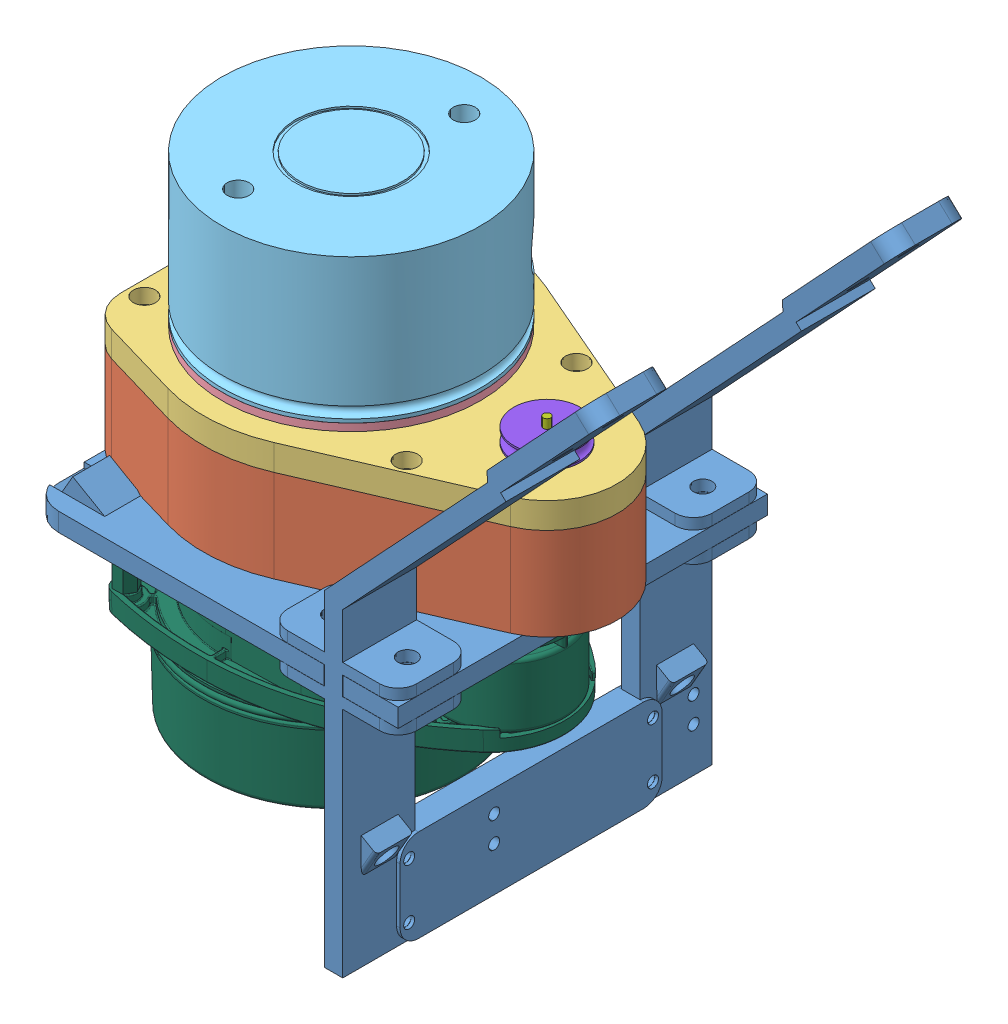
SolidWorks assembly Lidar_support_v1.0, configuration Default. Lengths in mm.
Overall size (171.83 167.83 100).
18 component instances, 15 part files, 3 mates.
Components (placement in the parent):
- Lidar_support-1: Lidar_support [Default] at origin size (155.02 167.83 100)
- LidarBeta-1: LidarBeta [Default] at (-121.1325 -107.1483 0) x (0 0 -1) z (1 0 0) size (85.95 74.01 114.97)
  - Cover_base-1: Cover_base [Default] at origin size (80 25 112)
  - Cover_top-1: Cover_top [Default] at origin size (80 8 112)
  - Head_base-1: Head_base [Default] at (0 37.0834 0) x (-0.258111 0 0.966115) z (-0.966115 0 -0.258111) size (70 58 70)
  - Head_top-1: Head_top [Default] at (0 15.2712 0) x (0.966115 0 0.258111) z (-0.258111 0 0.966115) size (70 39 70)
  - 6810-1: 6810 [Default] at (0 40.5782 0) x (0 1 0) z (0.911895 0 -0.410424) size (7.01 65 65)
  - RF-530-1: RF-530 [Default] at (0 22.073 53) size (33 31.5 33)
  - Pulley-1: Pulley [Default] at (0 -2.4896 0) size (18 4 18)
  - Slipring_v1.1-1: Slipring_v1.1 [Default] at (0 46.0834 0) x (-0.672958 0 -0.739681) z (-0.739681 0 0.672958) size (22 17 22)
  - Lidar_PCB-1: Lidar_PCB [Default] at (0 14.073 0) size (64 7.6 60)
  - Lidar_Lite_V2-1: Lidar_Lite_V2 [Default] at (-19.3223 65.0834 -5.1622) x (0.258111 0 -0.966115) z (0.966115 0 0.258111) size (48 35.4 39.5)
    - Garmin_Lidar_Lite_3.step-1: Garmin_Lidar_Lite_3.step [Default] at origin size (48 35.4 39.5)
      - Garmin_Lidar_Lite_31.step-1: Garmin_Lidar_Lite_31.step [Default] at origin size (48 35.4 5)
      - Garmin_Lidar_Lite_32.step-1: Garmin_Lidar_Lite_32.step [Default] at origin size (48 20 37)
      - Garmin_Lidar_Lite_33.step-1: Garmin_Lidar_Lite_33.step [Default] at origin size (12.5 4.5 2)
      - Garmin_Lidar_Lite_34.step-1: Garmin_Lidar_Lite_34.step [Default] at origin size (10.35 3.3 4.35)
- RPLidar-1: RPLidar [Default] at (-32.1069 619.6171 130.7152) x (0.999695 0 -0.024707) z (-0.024707 0 -0.999695) size (116.38 53.5 95.72)
Mates (geometry in assembly coordinates):
- Coincident1: coincident: plane of Lidar_support-1 through (0 -95.0752 50) normal (0 1 0); plane of ? through (-151.1325 -95.0752 22.5) normal (0 -1 0)
- Tangent1: tangent: plane of assembly; plane of Lidar_support-1 through (0 -100.0752 50) normal (0 -1 0); face of RPLidar-1
- Coincident3: coincident: plane of ? through (-121.1325 -107.1483 0) normal (0 0 -1); plane of assembly through (0 0 0) normal (0 0 1)
